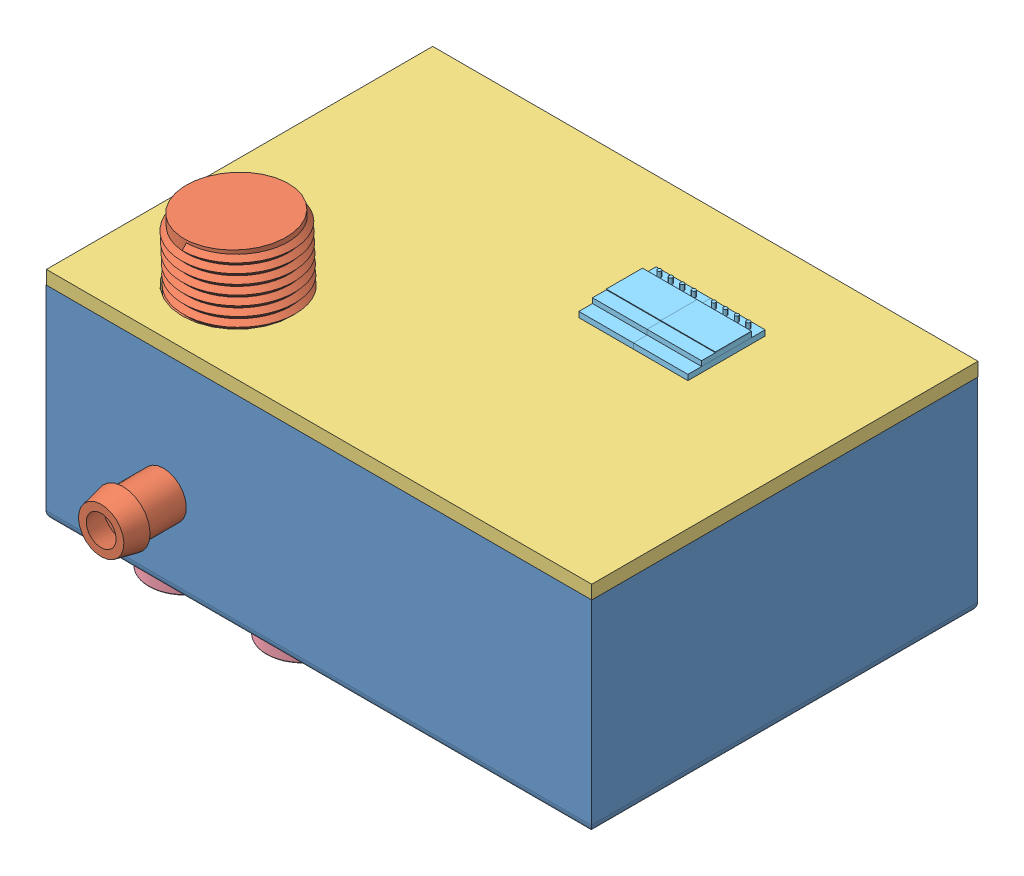
SolidWorks assembly Assem1, configuration Default. Lengths in mm.
Overall size (120.09 69.36 98.73).
9 component instances, 8 part files, 13 mates.
Components (placement in the parent):
- box_base-1: box_base [Default] at (6.3695 43.0804 110.3762) size (120 45 85)
- solenoid-1: solenoid [Default] at (-27.7608 61.0804 118.8333) x (-0.046313 0.998927 0) z (0.998927 0.046313 0) size (59 74.29 30)
- lid-1: lid [Default] at (6.4601 88.0804 110.3762) size (120 3 85)
- Ultra Sonic Sensor-1: Ultra Sonic Sensor [Default] at (-46.3688 50.0804 149.7637) x (1 0 0) z (0 0 -1) size (45.7 17.21 26.3)
- 042oled-1: 042oled [Varsayılan] at (32.2491 91.0804 94.9983) x (1 0 0) z (0 1 0) size (12 17 10.66)
- 042oled-2: 042oled [Varsayılan] at (20.2491 91.0804 94.9983) x (1 0 0) z (0 1 0) size (12 17 10.66)
- LD1263PWM-AT104XH11-85-1: LD1263PWM-AT104XH11-85 [По умолчанию] at (3.6393 46.5804 93.2137) x (-1 0 0) z (0 0 -1) size (93.5 7 32.5)
- HC05-1: HC05 [Default] at (32.4704 46.0804 122.4637) x (1 0 0) z (0 1 0) size (26.7 13 2.5)
- Power Converter-1: Power Converter [Default] at (41.6638 59.6356 126.2562) size (61 23.5 27)
Mates (geometry in assembly coordinates):
- Concentric1: concentric aligned: cylinder of box_base-1 through (-27.7608 61.0804 194.8762) axis (0 0 -1) radius 5; cylinder of solenoid-1 through (-27.7608 61.0804 161.8333) axis (0 0 -1) radius 5
- Coincident1: coincident aligned: plane of box_base-1 through (66.3695 88.0804 152.8762) normal (0 0 1); plane of lid-1 through (66.4601 91.0804 152.8762) normal (0 0 1)
- Coincident2: coincident anti-aligned: plane of box_base-1 through (6.3695 88.0804 110.3762) normal (0 1 0); plane of lid-1 through (6.4601 88.0804 110.3762) normal (0 -1 0)
- Coincident5: coincident anti-aligned: plane of box_base-1 through (6.3695 46.0804 110.3762) normal (0 1 0); plane of Ultra Sonic Sensor-1 through (-26.9188 46.0804 148.0637) normal (0 -1 0)
- Coincident6: coincident anti-aligned: plane of lid-1 through (6.4601 91.0804 110.3762) normal (0 1 0); plane of 042oled-1 through (32.2491 91.0804 94.9983) normal (0 -1 0)
- Coincident7: coincident anti-aligned: plane of lid-1 through (6.4601 91.0804 110.3762) normal (0 1 0); plane of 042oled-2 through (20.2491 91.0804 94.9983) normal (0 -1 0)
- Coincident11: coincident aligned: plane of 042oled-1 through (38.2491 92.2804 103.4983) normal (0 0 1); plane of 042oled-2 through (26.2491 92.2804 103.4983) normal (0 0 1)
- Coincident12: coincident anti-aligned: plane of 042oled-1 through (26.2491 92.2804 103.4983) normal (-1 0 0); plane of 042oled-2 through (26.2491 92.2804 103.4983) normal (1 0 0)
- Coincident13: coincident anti-aligned: plane of box_base-1 through (6.3695 46.0804 110.3762) normal (0 1 0); plane of LD1263PWM-AT104XH11-85-1 through (3.6393 46.0804 93.2137) normal (0 -1 0)
- Coincident14: coincident anti-aligned: plane of box_base-1 through (6.3695 46.0804 110.3762) normal (0 1 0); plane of HC05-1 through (32.4704 46.0804 122.4637) normal (0 -1 0)
- Coincident15: coincident anti-aligned: plane of box_base-1 through (6.3695 46.0804 110.3762) normal (0 1 0); plane of Power Converter-1 through (27.3643 46.0804 122.7316) normal (0 -1 0)
- Coincident16: coincident anti-aligned: plane of LD1263PWM-AT104XH11-85-1 through (-43.1107 47.0804 109.4637) normal (0 0 1); plane of HC05-1 through (32.4704 47.5804 109.4637) normal (0 0 -1)
- Coincident17: coincident anti-aligned: plane of HC05-1 through (32.4704 47.5804 122.4637) normal (0 0 1); plane of Power Converter-1 through (-2.6357 51.5804 122.4637) normal (0 0 -1)
